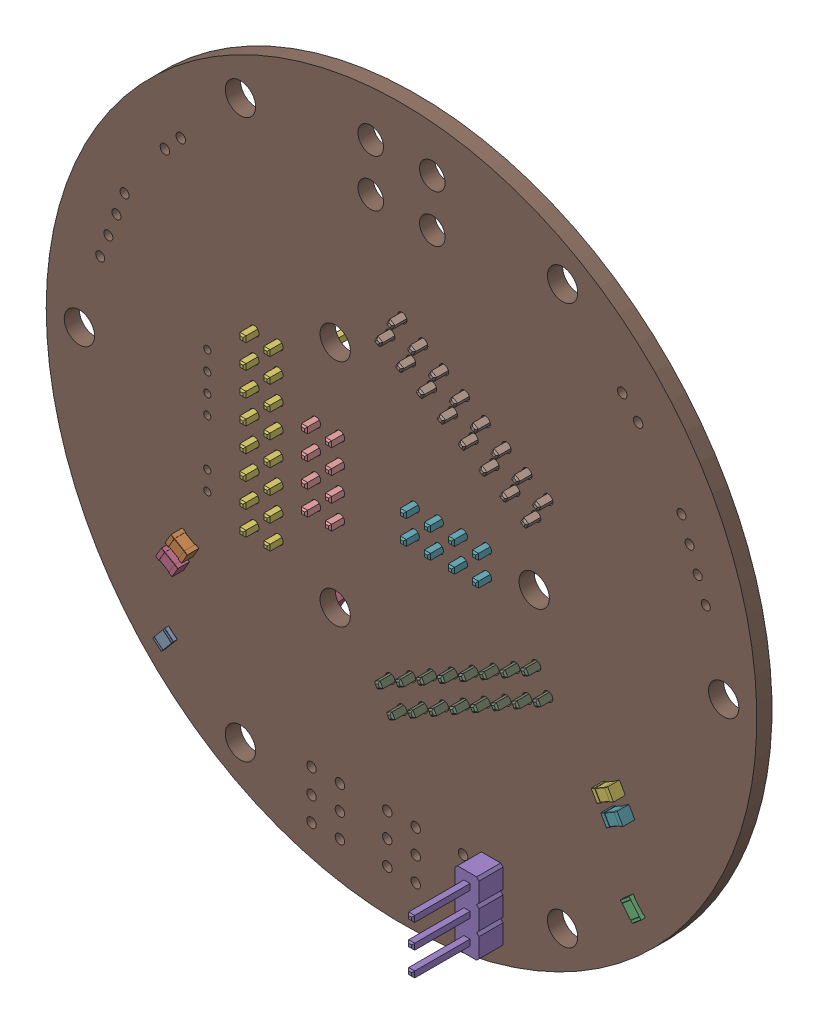
SolidWorks assembly Toolhead Board Breakout, configuration Default. Lengths in mm.
Overall size (75 75 18.78).
45 component instances, 7 part files, 0 mates.
Components (placement in the parent):
- R_0805_2012Metric-1: R_0805_2012Metric [Default] at (50.3109 -98.6672 1.65) x (0.642788 0.766044 0) z (0 0 1) size (2 1.2 0.45)
  - R_0805_2012Metric-1: R_0805_2012Metric [Default] at origin size (2 1.2 0.45)
- JST_PH_B2B-PH-K_1x02_P2.00mm_Vertical-1: JST_PH_B2B-PH-K_1x02_P2.00mm_Vertical [Default] at (54.5 -83.25 1.65) x (0 1 0) z (0 0 1) (suppressed, hidden)
- C_0805_2012Metric-1: C_0805_2012Metric [Default] at (52.5044 -88.8675 1.65) x (0.866025 -0.5 0) z (0 0 1) size (2 1.25 1.25)
  - C_0805_2012Metric-1: C_0805_2012Metric [Default] at origin size (2 1.25 1.25)
- R_0805_2012Metric-2: R_0805_2012Metric [Default] at (99.6891 -98.6672 1.65) x (0.642788 -0.766044 0) z (0 0 1) size (2 1.2 0.45)
  - R_0805_2012Metric-1: R_0805_2012Metric [Default] at origin size (2 1.2 0.45)
- JST_XH_B2B-XH-A_1x02_P2.50mm_Vertical-1: JST_XH_B2B-XH-A_1x02_P2.50mm_Vertical [Default] at (51.7028 -52.3411 1.65) x (-0.669131 -0.743145 0) z (0 0 1) (suppressed, hidden)
- C_0805_2012Metric-2: C_0805_2012Metric [Default] at (51.5044 -90.5995 1.65) x (0.866025 -0.5 0) z (0 0 1) size (2 1.25 1.25)
  - C_0805_2012Metric-1: C_0805_2012Metric [Default] at origin size (2 1.25 1.25)
- JST_XH_B4B-XH-A_1x04_P2.50mm_Vertical-1: JST_XH_B4B-XH-A_1x04_P2.50mm_Vertical [Default] at (104.545 -60.3008 1.65) x (0.34202 -0.939693 0) z (0 0 1) (suppressed, hidden)
- PinHeader_1x03_P2.54mm_Vertical-1: PinHeader_1x03_P2.54mm_Vertical [Default] at (68.5 -102.95 1.65) size (2.54 7.62 11.54) (suppressed, hidden)
  - PinHeader_1x03_P254mm_Vertical-1: PinHeader_1x03_P254mm_Vertical [Default] at origin size (2.54 7.62 11.54)
- JST_PH_B4B-PH-K_1x04_P2.00mm_Vertical-1: JST_PH_B4B-PH-K_1x04_P2.00mm_Vertical [Default] at (54.5 -76.29 1.65) x (0 1 0) z (0 0 1) (suppressed, hidden)
- JST_XH_B2B-XH-A_1x02_P2.50mm_Vertical-2: JST_XH_B2B-XH-A_1x02_P2.50mm_Vertical [Default] at (99.97 -54.1989 1.65) x (-0.669131 0.743145 0) z (0 0 1) (suppressed, hidden)
- PinHeader_1x03_P2.54mm_Vertical-2: PinHeader_1x03_P2.54mm_Vertical [Default] at (76.5 -102.95 1.65) size (2.54 7.62 11.54) (suppressed, hidden)
  - PinHeader_1x03_P254mm_Vertical-1: PinHeader_1x03_P254mm_Vertical [Default] at origin size (2.54 7.62 11.54)
- JST_XH_B4B-XH-A_1x04_P2.50mm_Vertical-2: JST_XH_B4B-XH-A_1x04_P2.50mm_Vertical [Default] at (45.7661 -60.369 1.65) x (-0.34202 -0.939693 0) z (0 0 1) (suppressed, hidden)
- PinHeader_1x03_P2.54mm_Vertical-3: PinHeader_1x03_P2.54mm_Vertical [Default] at (73.5 -102.95 1.65) size (2.54 7.62 11.54) (suppressed, hidden)
  - PinHeader_1x03_P254mm_Vertical-1: PinHeader_1x03_P254mm_Vertical [Default] at origin size (2.54 7.62 11.54)
- PinHeader_1x03_P2.54mm_Vertical-4: PinHeader_1x03_P2.54mm_Vertical [Default] at (84.5 -102.95 1.65) size (2.54 7.62 11.54)
  - PinHeader_1x03_P254mm_Vertical-1: PinHeader_1x03_P254mm_Vertical [Default] at origin size (2.54 7.62 11.54)
- C_0805_2012Metric-3: C_0805_2012Metric [Default] at (97.4956 -88.8675 1.65) x (-0.866025 -0.5 0) z (0 0 1) size (2 1.25 1.25)
  - C_0805_2012Metric-1: C_0805_2012Metric [Default] at origin size (2 1.25 1.25)
- PinHeader_1x03_P2.54mm_Vertical-5: PinHeader_1x03_P2.54mm_Vertical [Default] at (81.5 -102.95 1.65) size (2.54 7.62 11.54) (suppressed, hidden)
  - PinHeader_1x03_P254mm_Vertical-1: PinHeader_1x03_P254mm_Vertical [Default] at origin size (2.54 7.62 11.54)
- C_0805_2012Metric-4: C_0805_2012Metric [Default] at (98.4956 -90.5995 1.65) x (-0.866025 -0.5 0) z (0 0 1) size (2 1.25 1.25)
  - C_0805_2012Metric-1: C_0805_2012Metric [Default] at origin size (2 1.25 1.25)
- PinHeader_1x03_P2.54mm_Vertical-6: PinHeader_1x03_P2.54mm_Vertical [Default] at (65.5 -102.95 1.65) size (2.54 7.62 11.54) (suppressed, hidden)
  - PinHeader_1x03_P254mm_Vertical-1: PinHeader_1x03_P254mm_Vertical [Default] at origin size (2.54 7.62 11.54)
- TO-263-3_TabPin2-1: TO-263-3_TabPin2 [Default] at (92.3665 -92.9835 -0.05) x (-0.866025 -0.5 0) z (0 0 -1) size (15 10 4.42)
  - CQ assembly-1: CQ assembly [Default] at origin size (15 10 4.42)
- TO-263-3_TabPin2-2: TO-263-3_TabPin2 [Default] at (57.6335 -92.9835 -0.05) x (0.866025 -0.5 0) z (0 0 -1) size (15 10 4.42)
  - CQ assembly-1: CQ assembly [Default] at origin size (15 10 4.42)
- PinHeader_2x08_P2.54mm_Vertical-1: PinHeader_2x08_P2.54mm_Vertical [Default] at (62 -66.11 -0.05) x (-1 0 0) z (0 0 -1) size (5.08 20.32 11.54)
  - PinHeader_2x08_P254mm_Vertical-1: PinHeader_2x08_P254mm_Vertical [Default] at origin size (5.08 20.32 11.54)
- PinHeader_2x04_P2.54mm_Vertical-1: PinHeader_2x04_P2.54mm_Vertical [Default] at (84 -76.27 -0.05) x (0 1 0) z (0 0 -1) size (5.08 10.16 11.54)
  - PinHeader_2x04_P254mm_Vertical-1: PinHeader_2x04_P254mm_Vertical [Default] at origin size (5.08 10.16 11.54)
- PinHeader_2x08_P2.54mm_Vertical-2: PinHeader_2x08_P2.54mm_Vertical [Default] at (89.199 -68.1867 -0.05) x (0.5 0.866025 0) z (0 0 -1) size (5.08 20.32 11.54)
  - PinHeader_2x08_P254mm_Vertical-1: PinHeader_2x08_P254mm_Vertical [Default] at origin size (5.08 20.32 11.54)
- PinHeader_2x08_P2.54mm_Vertical-3: PinHeader_2x08_P2.54mm_Vertical [Default] at (73.801 -90.7033 -0.05) x (0.5 -0.866025 0) z (0 0 -1) size (5.08 20.32 11.54)
  - PinHeader_2x08_P254mm_Vertical-1: PinHeader_2x08_P254mm_Vertical [Default] at origin size (5.08 20.32 11.54)
- PinHeader_2x04_P2.54mm_Vertical-2: PinHeader_2x04_P2.54mm_Vertical [Default] at (68.5 -71.19 -0.05) x (-1 0 0) z (0 0 -1) size (5.08 10.16 11.54)
  - PinHeader_2x04_P254mm_Vertical-1: PinHeader_2x04_P254mm_Vertical [Default] at origin size (5.08 10.16 11.54)
- _autosave-Toolhead Board Breakout_PCB-1: _autosave-Toolhead Board Breakout_PCB [Default] at origin size (75 75 1.6)
